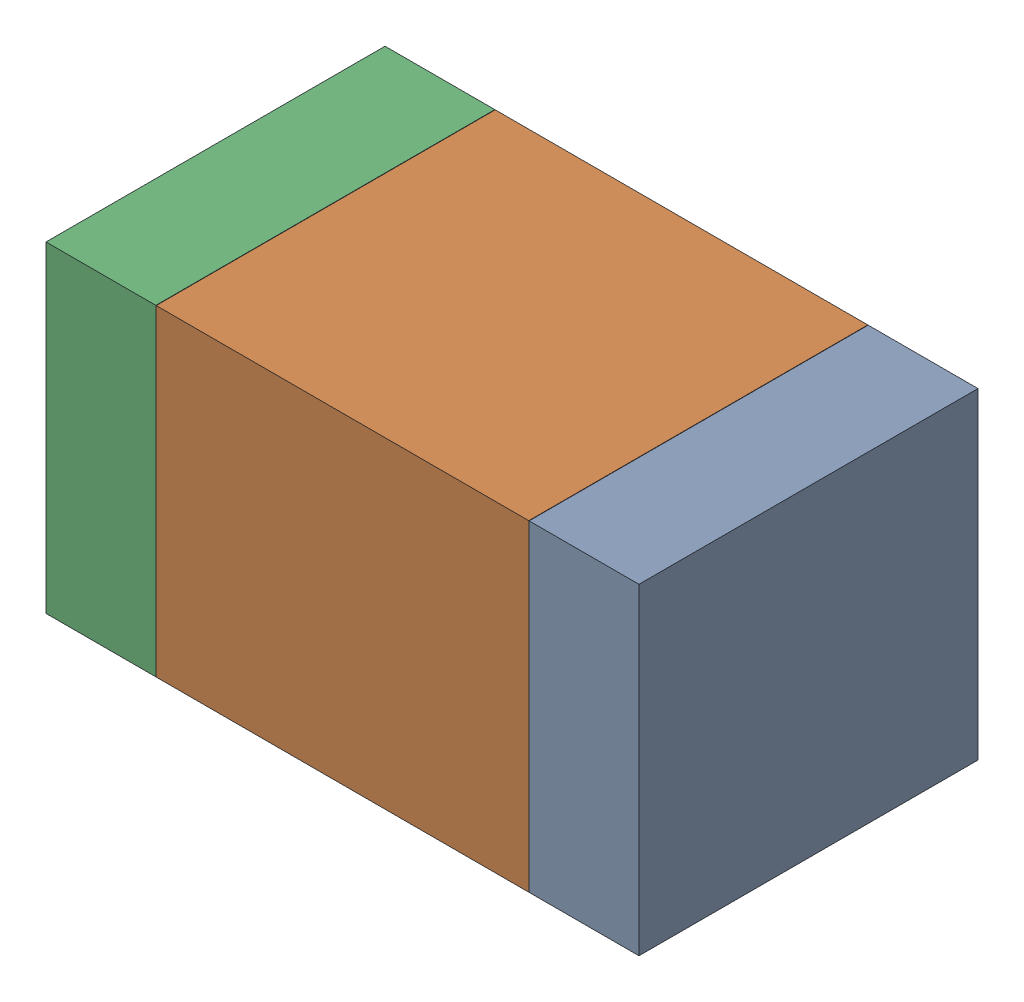
SolidWorks assembly R40, configuration Default. Lengths in mm.
Overall size (1.75 0.95 1).
6 component instances, 2 part files, 0 mates.
Components (placement in the parent):
- 6575498272-1: 6575498272 [Default] at (45.9245 9.398 0) size (0.32 0.95 1)
  - Extruded_8-1: Extruded_8 [Default] at origin size (0.32 0.95 1)
- 6575498112-1: 6575498112 [Default] at (45.212 9.398 0) size (1.1 0.95 1)
  - Extruded_9-1: Extruded_9 [Default] at origin size (1.1 0.95 1)
- 6575498272-2: 6575498272 [Default] at (44.4995 9.398 0) size (0.32 0.95 1)
  - Extruded_8-1: Extruded_8 [Default] at origin size (0.32 0.95 1)
